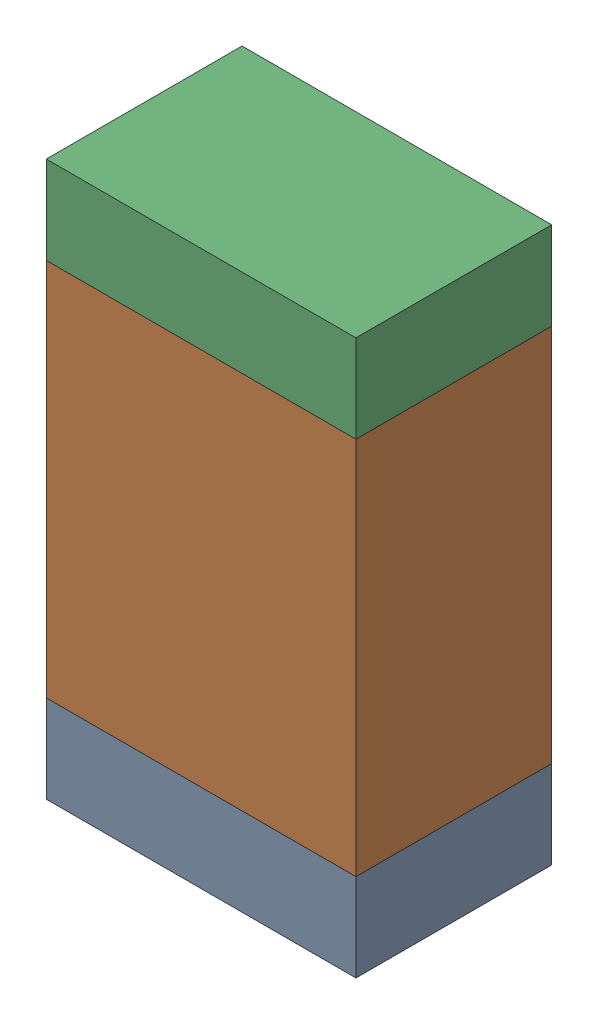
SolidWorks assembly R05-2, configuration Default. Lengths in mm.
Overall size (0.95 1.7 0.6).
6 component instances, 2 part files, 0 mates.
Components (placement in the parent):
- 959206216-2-1: 959206216-2 [Default] at (123.9521 73.9609 0) size (0.95 0.27 0.6)
  - Extruded-62-1: Extruded-62 [Default] at origin size (0.95 0.27 0.6)
- 959206352-2-1: 959206352-2 [Default] at (123.9521 74.6759 0) size (0.95 1.16 0.6)
  - Extruded-63-1: Extruded-63 [Default] at origin size (0.95 1.16 0.6)
- 959206216-2-2: 959206216-2 [Default] at (123.9521 75.3909 0) size (0.95 0.27 0.6)
  - Extruded-62-1: Extruded-62 [Default] at origin size (0.95 0.27 0.6)
